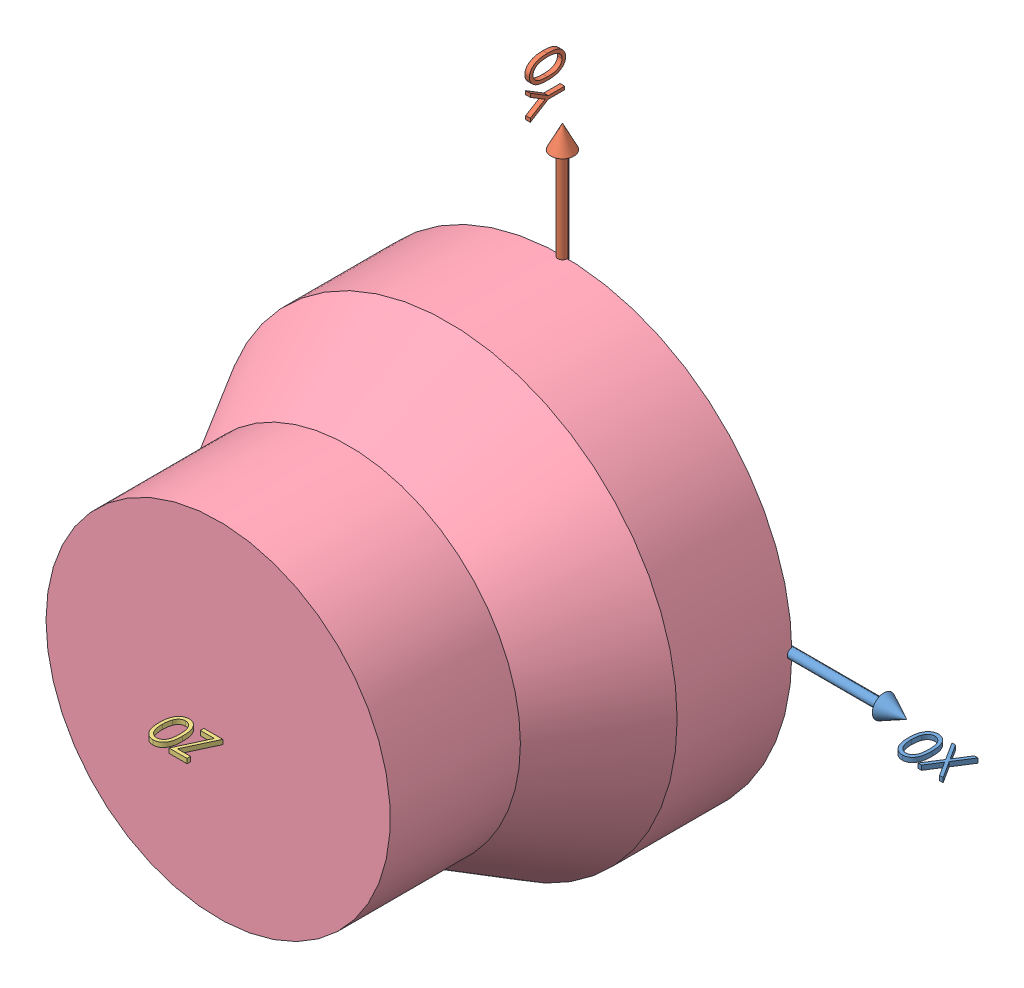
SolidWorks assembly base_link, configuration Default. Lengths in mm.
Overall size (281.06 280.58 177.88).
5 component instances, 4 part files, 6 mates.
Components (placement in the parent):
- frame0_xyz-1: frame0_xyz [Default] at origin size (191.71 185.58 177.88)
  - frame_arrowX0-1: frame_arrowX0 [Default] x (0 0 -1) z (1 0 0) size (20.38 10 181.06)
  - frame_arrowY0-2: frame_arrowY0 [Default] x (0 0 1) z (0 1 0) size (20.38 10 180.58)
  - frame_arrowZ0-3: frame_arrowZ0 [Default] x (0 -1 0) z (0 0 1) size (10 20.19 172.88)
- base_link-1: base_link [Default] at origin size (200 200 150)
Mates (geometry in assembly coordinates):
- Coincident4: coincident aligned: plane of frame0_xyz-1 through (0 0 0) normal (0 0 1); plane of link0-1 through (0 0 0) normal (0 0 1)
- Coincident5: coincident aligned: plane of frame0_xyz-1 through (0 0 0) normal (0 1 0); plane of link0-1 through (0 0 0) normal (0 1 0)
- Coincident6: coincident aligned: plane of frame0_xyz-1 through (0 0 0) normal (1 0 0); plane of link0-1 through (0 0 0) normal (1 0 0)
- Coincident7: coincident aligned: plane of frame0_xyz-1 through (0 0 0) normal (0 0 1)
- Coincident8: coincident aligned: plane of frame0_xyz-1 through (0 0 0) normal (0 1 0)
- Coincident9: coincident aligned: plane of frame0_xyz-1 through (0 0 0) normal (1 0 0)
